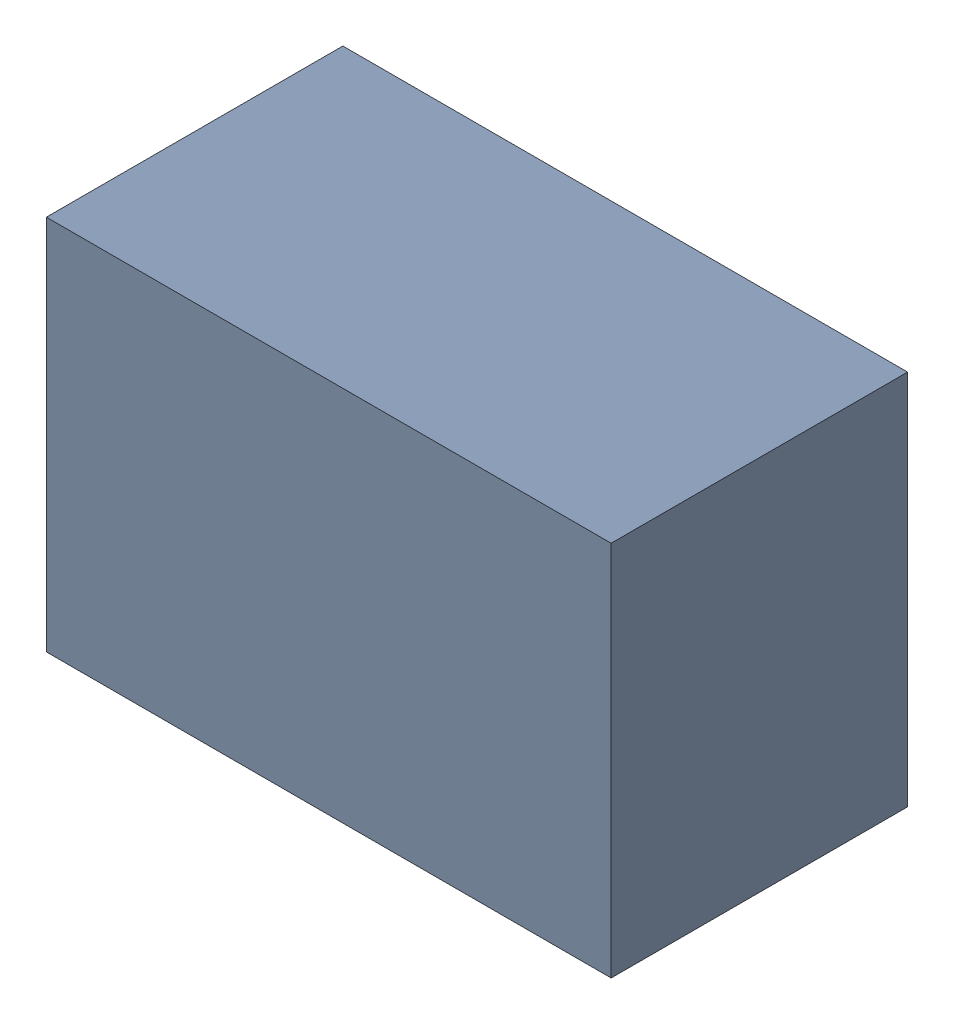
SolidWorks assembly USB45_L1, configuration Default. Lengths in mm.
Overall size (2.29 1.52 1.2).
2 component instances, 1 part files, 0 mates.
Components (placement in the parent):
- 402659088-1: 402659088 [Default] at (158.75 43.815 0) size (2.29 1.52 1.2)
  - Extruded_28-1: Extruded_28 [Default] at origin size (2.29 1.52 1.2)
